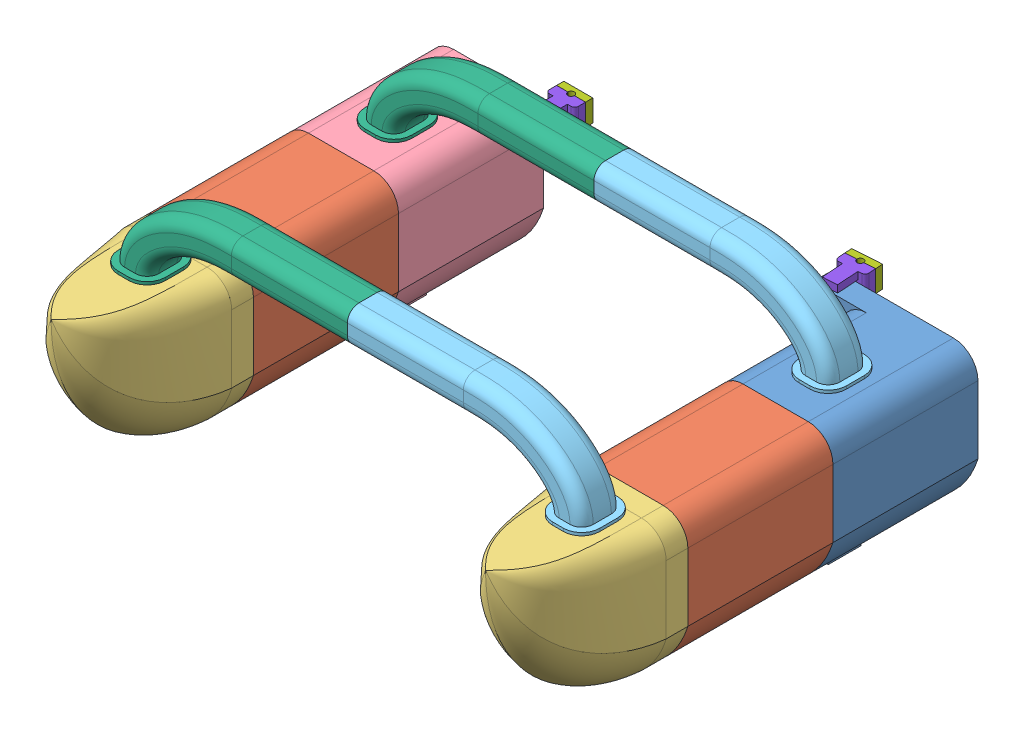
SolidWorks assembly Assemblageboatvirsion2, configuration Défaut. Lengths in mm.
Overall size (767.24 323.04 636.92).
20 component instances, 8 part files, 13 mates.
Components (placement in the parent):
- Assemblagehull1-1: Assemblagehull1 [Défaut] at (-9.9267 302.1646 611.8727) size (203.18 223.75 607.68)
  - body_back_2-1: body_back_2 [Défaut] at (59.9179 -48.2398 110) size (198 212 220)
  - body_mid-1: body_mid [Défaut] at (59.9179 -48.2398 310) size (158 208.49 220)
  - body_front-1: body_front [Défaut] at (59.9179 -48.2398 510) size (168.2 223.75 207.68)
- Assemblagehull2-1: Assemblagehull2 [Défaut] at (-540.1584 218.1203 669.6338) size (203.03 223.75 607.68)
  - body_back2-1: body_back2 [Défaut] at (-8.8859 35.8046 52.2389) size (198 212 220)
  - body_mid-1: body_mid [Défaut] at (-8.8859 35.8046 252.2389) size (158 208.49 220)
  - body_front-1: body_front [Défaut] at (-8.8859 35.8046 452.2389) size (168.2 223.75 207.68)
- Assemblage_support-1: Assemblage_support [Défaut] at (-546.9504 403.2709 986.6766) x (0 0 -1) z (1 0 0) size (75 117.02 664.04)
  - support_numero2-1: support_numero2 [Défaut] at (141.9181 50.18 169.7744) size (75 117.02 352.02)
  - support_numero1-1: support_numero1 [Défaut] at (142.6897 50.18 169.7744) x (-1 0 0) z (0 0 -1) size (75 117.02 332.02)
- Assemblage_support-2: Assemblage_support [Défaut] at (-546.9504 403.2709 1326.6766) x (0 0 -1) z (1 0 0) size (75 117.02 664.04)
  - support_numero2-1: support_numero2 [Défaut] at (141.9181 50.18 169.7744) size (75 117.02 352.02)
  - support_numero1-1: support_numero1 [Défaut] at (142.6897 50.18 169.7744) x (-1 0 0) z (0 0 -1) size (75 117.02 332.02)
- Assemblage support fillet-1: Assemblage support fillet [Défaut] at (-164.556 309.4509 703.6012) x (0.997755 0 -0.066975) z (0 1 0) size (40 55 50)
  - support_fillet2_virsion2-1: support_fillet2_virsion2 [Défaut] at (-4.3035 15.6137 40) size (40 10 30)
  - support_fillet1_virsion2-1: support_fillet1_virsion2 [Défaut] at (-4.3035 -14.3863 70) x (1 0 0) z (0 0 -1) size (40 45 50)
- Assemblage support fillet-2: Assemblage support fillet [Défaut] at (-563.3903 309.4509 704.4864) x (1 0 0) z (0 1 0) size (40 55 50)
  - support_fillet2_virsion2-1: support_fillet2_virsion2 [Défaut] at (-4.3035 15.6137 40) size (40 10 30)
  - support_fillet1_virsion2-1: support_fillet1_virsion2 [Défaut] at (-4.3035 -14.3863 70) x (1 0 0) z (0 0 -1) size (40 45 50)
Mates (geometry in assembly coordinates):
- Coïncidente3: coincident: plane of Assemblagehull1-1/body_back_2-1 through (-32.6583 369.4509 921.8727) normal (0 1 0); plane of Assemblage_support-1/support_numero2-1 through (-70.1583 369.4509 831.8727) normal (0 -1 0)
- Coaxiale1: concentric: cylinder of Assemblagehull1-1/body_back_2-1 through (-70.1583 359.4509 856.8727) axis (0 1 0) radius 10; cylinder of Assemblage_support-1/support_numero2-1 through (-70.1583 374.4509 856.8727) axis (0 -1 0) radius 10
- Coaxiale2: concentric anti-aligned: cylinder of Assemblagehull1-1/body_back_2-1 through (-85.1583 359.4509 856.8727) axis (0 1 0) radius 10; cylinder of Assemblage_support-1/support_numero2-1 through (-85.1583 374.4509 856.8727) axis (0 -1 0) radius 10
- Coaxiale3: concentric: cylinder of Assemblagehull2-1/body_back2-1 through (-669.1938 359.4509 856.8727) axis (0 1 0) radius 10; cylinder of Assemblage_support-1/support_numero1-1 through (-669.1938 374.4509 856.8727) axis (0 -1 0) radius 12
- Coaxiale4: concentric: cylinder of Assemblagehull2-1/body_back2-1 through (-684.1938 359.4509 856.8727) axis (0 1 0) radius 10; cylinder of Assemblage_support-1/support_numero1-1 through (-684.1938 374.4509 856.8727) axis (0 -1 0) radius 12
- Coïncidente4: coincident anti-aligned: plane of Assemblagehull2-1/body_back2-1 through (-631.6938 369.4509 921.8727) normal (0 1 0); plane of Assemblage_support-1/support_numero1-1 through (-684.1938 369.4509 856.8727) normal (0 -1 0)
- Coaxiale5: concentric: cylinder of Assemblagehull2-1/body_front-1 through (-669.1938 359.4509 1196.8727) axis (0 1 0) radius 10; cylinder of Assemblage_support-2/support_numero1-1 through (-669.1938 374.4509 1196.8727) axis (0 -1 0) radius 12
- Coaxiale6: concentric: cylinder of Assemblagehull2-1/body_front-1 through (-684.1938 359.4509 1196.8727) axis (0 1 0) radius 10; cylinder of Assemblage_support-2/support_numero1-1 through (-684.1938 374.4509 1196.8727) axis (0 -1 0) radius 12
- Coïncidente5: coincident anti-aligned: plane of Assemblagehull2-1/body_front-1 through (-721.6938 369.4509 1151.8727) normal (0 1 0); plane of Assemblage_support-2/support_numero1-1 through (-684.1938 369.4509 1196.8727) normal (0 -1 0)
- Coaxiale7: concentric: cylinder of Assemblagehull1-1/body_back_2-1 through (-176.6583 324.4509 736.8727) axis (0 1 0) radius 6; cylinder of Assemblage support fillet-1/support_fillet1_virsion2-1 through (-176.6583 329.4509 736.8727) axis (0 1 0) radius 6
- Coïncidente6: coincident anti-aligned: plane of Assemblagehull1-1/body_back_2-1 through (-32.6583 369.4509 921.8727) normal (0 1 0); plane of Assemblage support fillet-1/support_fillet1_virsion2-1 through (-166.6583 369.4509 718.8727) normal (0 -1 0)
- Coaxiale8: concentric: cylinder of Assemblagehull2-1/body_back2-1 through (-577.6938 304.4509 736.8727) axis (0 1 0) radius 6; cylinder of Assemblage support fillet-2/support_fillet1_virsion2-1 through (-577.6938 329.4509 736.8727) axis (0 1 0) radius 6
- Coïncidente7: coincident anti-aligned: plane of Assemblagehull2-1/body_back2-1 through (-631.6938 369.4509 921.8727) normal (0 1 0); plane of Assemblage support fillet-2/support_fillet1_virsion2-1 through (-567.6938 369.4509 718.8727) normal (0 -1 0)
